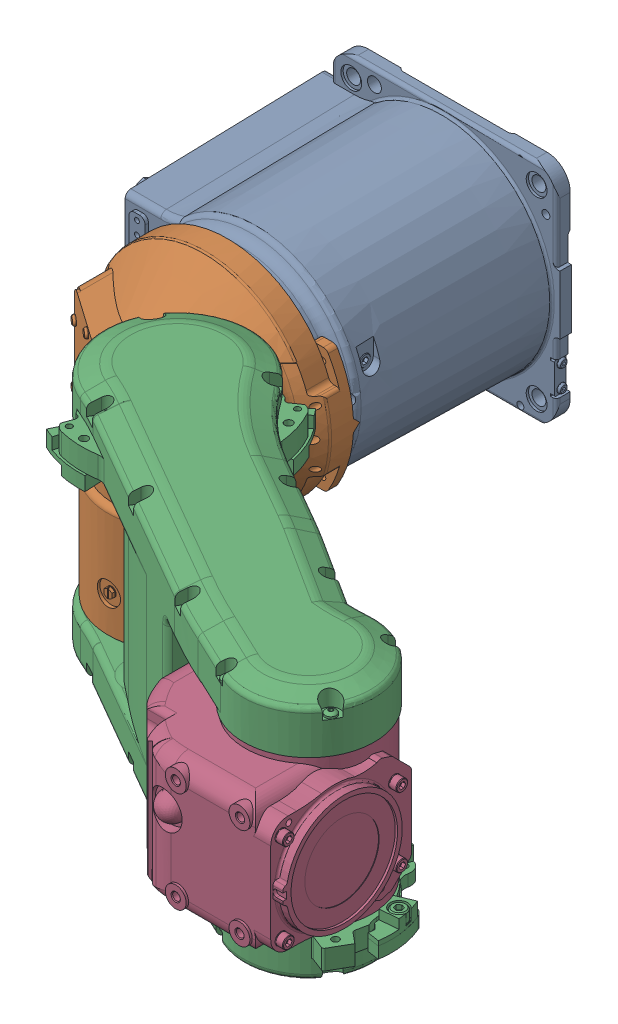
SolidWorks assembly ASSEMBLY_3_JOINTS, configuration Default. Lengths in mm.
Overall size (607.24 219.43 593.51).
4 component instances, 4 part files, 6 mates.
Components (placement in the parent):
- S5_BASE-1: S5_BASE [Default] at (9.2374 49.9985 210.4949) size (250.2 197 204.01)
- S5_ARM1-1: S5_ARM1 [Default] at (9.2374 49.9985 205.9949) x (-1 0 0) z (0 1 0) size (245.28 204.35 187)
- S5_ARM2-1: S5_ARM2 [Default] at (97.2374 51.9985 336.9949) x (-0.5 0 0.866025) z (0 1 0) size (164.19 450 219.43)
- S5_ARM3-1: S5_ARM3 [Default] at (365.7052 53.9985 491.9949) x (-1 0 0) z (0 1 0) size (170.51 155.5 134.01)
Mates (geometry in assembly coordinates):
- Coincident1: coincident anti-aligned: plane of S5_BASE-1 through (9.2374 49.9985 210.4949) normal (0 0 1); plane of S5_ARM1-1 through (9.2374 49.9985 210.4949) normal (0 0 -1)
- Concentric1: concentric aligned: cylinder of S5_BASE-1 through (9.2374 49.9985 17.9949) axis (0 0 1) radius 75; cylinder of S5_ARM1-1 through (9.2374 49.9985 205.9949) axis (0 0 1) radius 75
- Coincident2: coincident anti-aligned: plane of S5_ARM1-1 through (97.2374 -11.0015 391.9949) normal (0 -1 0); plane of S5_ARM2-1 through (97.2374 -11.0015 336.9949) normal (0 1 0)
- Concentric2: concentric aligned: cylinder of S5_ARM1-1 through (97.2374 -11.0015 336.9949) axis (0 1 0) radius 55; cylinder of S5_ARM2-1 through (97.2374 -23.5015 336.9949) axis (0 1 0) radius 50
- Coincident3: coincident anti-aligned: plane of S5_ARM2-1 through (365.7052 118.9985 491.9949) normal (0 -1 0); plane of S5_ARM3-1 through (365.7052 118.9985 491.9949) normal (0 1 0)
- Concentric3: concentric aligned: cylinder of S5_ARM2-1 through (365.7052 -19.0015 491.9949) axis (0 1 0) radius 50; cylinder of S5_ARM3-1 through (365.7052 -15.0015 491.9949) axis (0 1 0) radius 50
